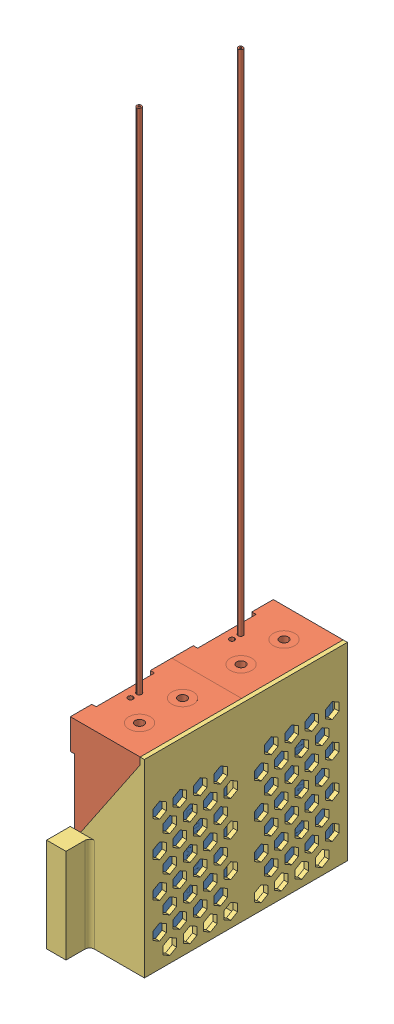
SolidWorks assembly 9V Battery EasyMini Assembly, configuration Default. Lengths in mm.
Overall size (21.89 55.89 73.96).
5 component instances, 3 part files, 22 mates.
Components (placement in the parent):
- 9v Duracell Body-7: 9v Duracell Body [Default] at (1.9612 36.4049 32.198) size (17.11 47.9 25.9)
- battery holder-1: battery holder [Default] at (-18.1868 28.5806 31.5055) x (0 1 0) z (0 0 -1) size (204.61 20.62 29.97)
- 9v Duracell Body-8: 9v Duracell Body [Default] at (1.9612 36.4049 0.841) size (17.11 47.9 25.9)
- battery holder-2: battery holder [Default] at (-18.1868 28.5806 1.5335) x (0 1 0) z (0 0 -1) size (204.61 20.62 29.97)
- EasyMini Battery Cover-5: EasyMini Battery Cover [Default] at (-18.187 27.9406 1.537) x (0 0 -1) z (0 -1 0) size (73.96 21.89 55.89)
Mates (geometry in assembly coordinates):
- Coincident30: coincident anti-aligned: plane of battery holder-2 through (-15.1388 28.5806 1.5335) normal (1 0 0); plane of 9v Duracell Body-3 through (-12.1024 140.5818 177.932) normal (-0.676623 -0.685958 -0.26766)
- Coincident31: coincident anti-aligned: plane of battery holder-2 through (-18.1868 51.3136 1.5335) normal (0 -1 0); circle of 9v Duracell Body-3
- Tangent7: tangent anti-aligned: cylinder of battery holder-2 through (-6.3758 49.9166 7.8835) axis (0 1 0) radius 2.8575; plane of 9v Duracell Body-3 through (2.7511 136.8793 175.7446) normal (0.727487 -0.566603 -0.386941)
- Coincident54: coincident anti-aligned: plane of battery holder-2 through (2.438 28.5806 1.5335) normal (1 0 0); plane of EasyMini Battery Cover-3 through (21.4073 110.4428 155.9409) normal (0 -1 0)
- Coincident60: coincident anti-aligned: plane of battery holder-2 through (-15.1388 1.2756 1.5335) normal (0 -1 0); plane of EasyMini Battery Cover-3 through (-5.2677 111.7128 170.9304) normal (1 0 0)
- Coincident63: coincident aligned: plane of battery holder-2 through (-15.1388 28.5806 -13.4525) normal (0 0 -1); plane of EasyMini Battery Cover-3 through (49.3523 111.7128 170.9304) normal (0 0 1)
- Coincident71: coincident anti-aligned: plane of 9v Duracell Body-5 through (41.9203 92.866 131.8764) normal (0 -1 0); plane of battery holder-3 through (22.0373 92.866 121.6924) normal (0 1 0)
- Coincident72: coincident anti-aligned: plane of 9v Duracell Body-5 through (41.9203 94.866 107.9764) normal (0 0 -1); plane of battery holder-3 through (22.0373 110.4428 107.9764) normal (0 0 1)
- Coincident73: coincident anti-aligned: circle of 9v Duracell Body-5; plane of battery holder-3 through (44.7703 89.818 121.6924) normal (-1 0 0)
- Coincident74: coincident aligned: plane of EasyMini Battery Cover-3 through (49.3523 111.7128 106.7064) normal (0 0 -1); plane of battery holder-3 through (49.3423 91.088 106.7064) normal (0 0 -1)
- Parallel3: parallel aligned: plane of EasyMini Battery Cover-3 through (49.3523 111.7128 136.6854) normal (0 0 1); plane of battery holder-3 through (22.0373 92.866 136.6784) normal (0 0 1)
- Coincident76: coincident anti-aligned: plane of EasyMini Battery Cover-3 through (-5.2677 111.7128 106.7064) normal (1 0 0); plane of battery holder-3 through (-5.2677 92.866 121.6924) normal (-1 0 0)
- Coincident78: coincident anti-aligned: plane of EasyMini Battery Cover-3 through (21.4073 110.4428 121.6959) normal (0 -1 0); plane of battery holder-3 through (22.0373 110.4428 121.6924) normal (0 1 0)
- Coincident79: coincident anti-aligned: plane of 9v Duracell Body-3 through (-12.1024 140.5818 177.932) normal (-0.676623 -0.685958 -0.26766); plane of battery holder-4 through (-7.0587 143.9689 156.5013) normal (0.676623 0.685958 0.26766)
- Coincident80: coincident anti-aligned: circle of 9v Duracell Body-3; plane of battery holder-4 through (-6.5347 131.4998 175.7451) normal (-0.113768 0.456532 -0.882403)
- Tangent8: tangent anti-aligned: plane of 9v Duracell Body-3 through (8.9513 135.9924 174.4863) normal (-0.727487 0.566603 0.386941); cylinder of battery holder-4 through (5.9175 136.6415 175.2167) axis (0.113768 -0.456532 0.882403) radius 2.8575
- Coincident81: coincident anti-aligned: plane of 9v Duracell Body-7 through (-15.1388 5.9048 43.148) normal (-1 0 0); plane of battery holder-1 through (-15.1388 28.5806 31.5055) normal (1 0 0)
- Coincident82: coincident anti-aligned: plane of 9v Duracell Body-7 through (-6.5888 50.1049 37.748) normal (0 1 0); circle of battery holder-1
- Tangent9: tangent anti-aligned: plane of 9v Duracell Body-7 through (-8.2138 51.8549 34.998) normal (0 0 1); cylinder of battery holder-1 through (-6.3758 49.9166 37.8555) axis (0 1 0) radius 2.8575
- Coincident83: coincident anti-aligned: plane of battery holder-2 through (2.438 28.5806 1.5335) normal (1 0 0); plane of EasyMini Battery Cover-5 through (2.438 27.9406 1.537) normal (-1 0 0)
- Coincident84: coincident aligned: plane of battery holder-2 through (-15.1388 28.5806 -13.4525) normal (0 0 -1); plane of EasyMini Battery Cover-5 through (3.708 55.8856 -13.4525) normal (0 0 -1)
- Coincident85: coincident aligned: plane of battery holder-1 through (-16.9168 55.8856 46.4915) normal (0 1 0); plane of EasyMini Battery Cover-5 through (3.708 55.8856 -13.4525) normal (0 1 0)
